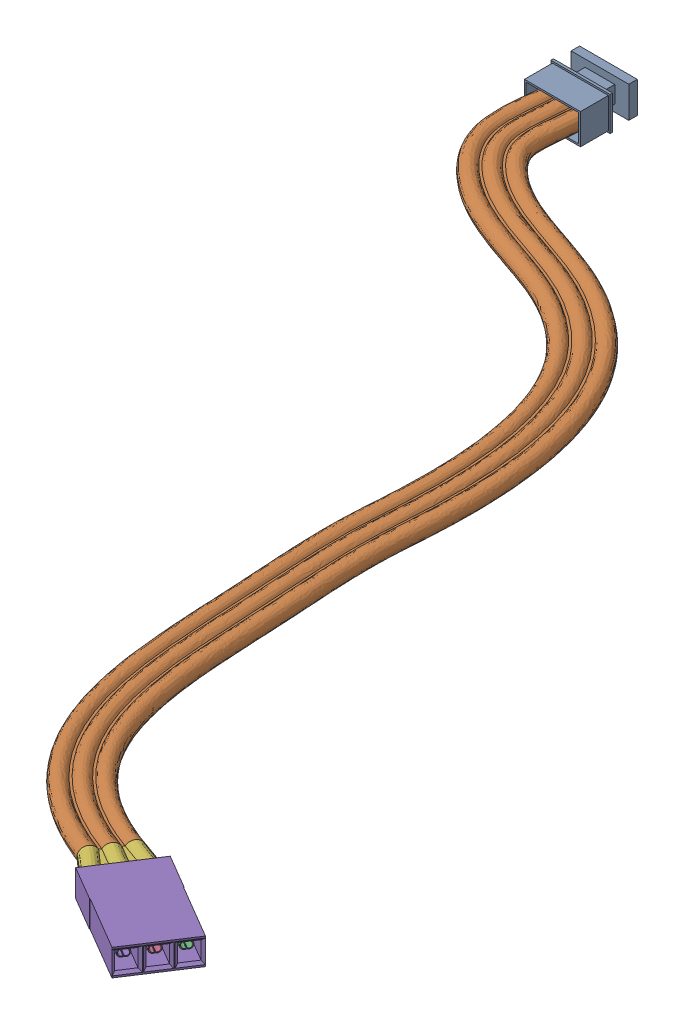
SolidWorks assembly filo completo 2, configuration Default. Lengths in mm.
Overall size (70.61 5.53 121.44).
4 component instances, 4 part files, 10 mates.
Components (placement in the parent):
- Connettore servom-3: Connettore servom [Default] at (4.831 6.0071 -0.15) x (0 -1 0) z (0 0 -1) size (4 7 6.6)
- filo2-1: filo2 [Default] at (1.331 4.0071 -0.15) size (55.3 4.19 108.32)
- Connettore fili-1: Connettore fili [Default] at (62.7834 7.2287 112.3122) x (0.526431 -0.016835 -0.850051) z (0.042718 -0.998017 0.046221) size (8.1 13 3)
- terminale fili-1: terminale fili [Default] at (53.2147 6.2461 110.7585) x (0.526431 -0.016835 -0.850051) z (-0.849144 -0.060644 -0.524668) size (7.41 2.02 5.7)
Mates (geometry in assembly coordinates):
- Coincidente22: coincident anti-aligned: plane of Connettore fili-1 through (64.339 5.0385 117.6716) normal (0.526431 -0.016835 -0.850051); plane of terminale fili-1 through (54.6582 6.3492 111.6504) normal (-0.526431 0.016835 0.850051)
- Coincidente23: coincident anti-aligned: plane of Connettore fili-1 through (64.339 5.0385 117.6716) normal (0.526431 -0.016835 -0.850051); plane of terminale fili-1 through (54.6582 6.3492 111.6504) normal (-0.526431 0.016835 0.850051)
- Coincidente24: coincident aligned: line of Connettore fili-1 through (53.2147 6.2461 110.7585) axis (0.526431 -0.016835 -0.850051); line of terminale fili-1 through (53.2147 6.2461 110.7585) axis (0.526431 -0.016835 -0.850051)
- Coincidente26: coincident aligned: line of Connettore fili-1 through (54.353 4.2164 109.1508) axis (-0.526431 0.016835 0.850051); line of terminale fili-1 through (53.8261 4.2333 110.0016) axis (-0.526431 0.016835 0.850051)
- Coincidente43: coincident: point of filo2-1
- Coincidente44: coincident anti-aligned: plane of Connettore servom-3 through (4.831 6.0071 -0.15) normal (0 0 1); plane of filo2-1 through (1.331 4.0071 -0.15) normal (0 0 -1)
- Coincidente45: coincident: circle of filo2-1
- Coincidente46: coincident anti-aligned: plane of terminale fili-1 through (51.8086 4.9433 105.5609) normal (-0.849144 -0.060644 -0.524668); plane of filo2-1 through (51.8086 4.9433 105.5609) normal (0.849144 0.060644 0.524668)
- Coincidente47: coincident: unknown of filo2-1; unknown of terminale fili-1
- Coincidente48: coincident: unknown of filo2-1; unknown of terminale fili-1
